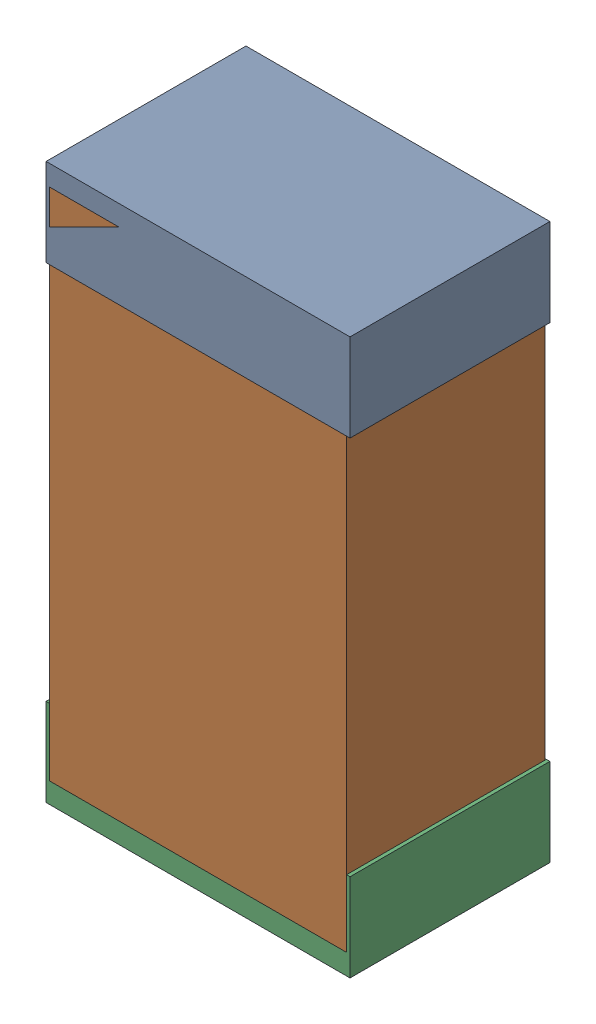
SolidWorks assembly R49Kanaloa_v2.0.0_Motor, configuration Default. Lengths in mm.
Overall size (1.3 2.38 0.85).
6 component instances, 2 part files, 0 mates.
Components (placement in the parent):
- 330415056-1: 330415056 [Default] at (51.054 151.368 -1.9574) size (1.3 0.38 0.85)
  - Extruded_2-1: Extruded_2 [Default] at origin size (1.3 0.38 0.85)
- 334787376-1: 334787376 [Default] at (51.054 150.368 -1.9524) size (1.27 2.2 0.85)
  - Extruded_16-1: Extruded_16 [Default] at origin size (1.27 2.2 0.85)
- 330415056-2: 330415056 [Default] at (51.054 149.368 -1.9574) size (1.3 0.38 0.85)
  - Extruded_2-1: Extruded_2 [Default] at origin size (1.3 0.38 0.85)
